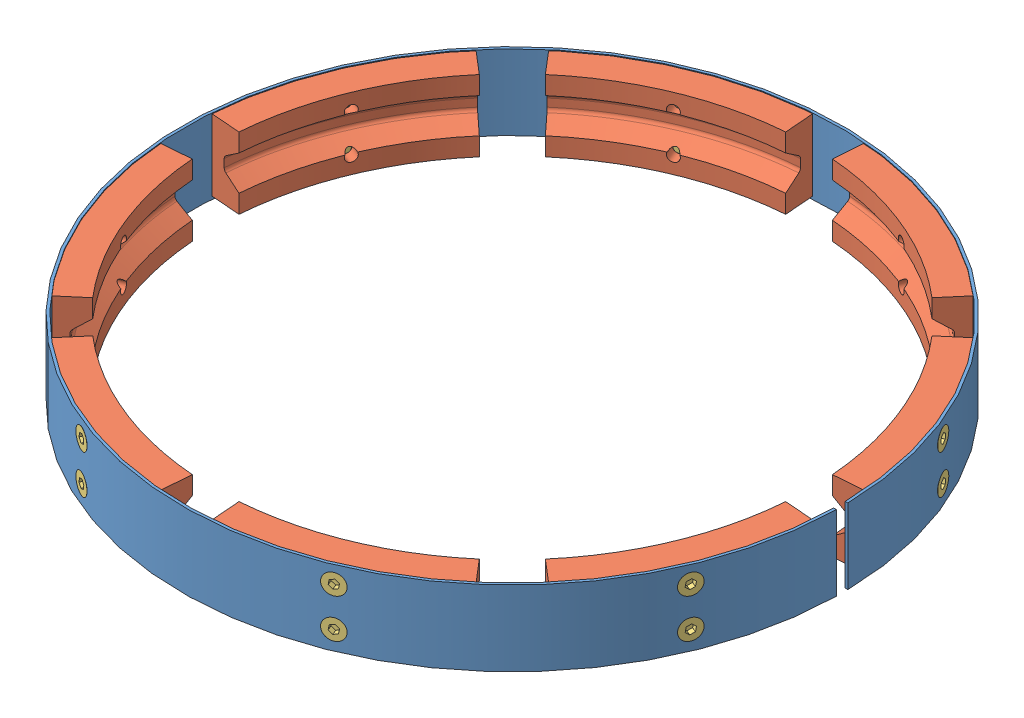
SolidWorks assembly Clampband, configuration Standard. Lengths in mm.
Overall size (127.25 14 127.25).
25 component instances, 3 part files, 6 mates.
Components (placement in the parent):
- R1-1_clampband_spring_steel-1: R1-1_clampband_spring_steel [Standard] at (28.2082 37.1213 114.6564) size (122.99 14 123)
- R1-4_clampband_clamp-1: R1-4_clampband_clamp [Standard] at (28.2082 37.3213 114.6564) x (0.92388 0 0.382683) z (-0.382683 0 0.92388) size (8.28 13.3 37.7)
- Fastener_SunkHead_M2_4-1: Fastener_SunkHead_M2_4 [Standard] at (-28.6104 33.6713 91.1214) x (0.376014 0.185879 -0.907779) z (0.071133 -0.982573 -0.171729) size (3.8 4 3.8)
- Fastener_SunkHead_M2_4-2: Fastener_SunkHead_M2_4 [Standard] at (-28.6104 40.9713 91.1214) x (0.376014 0.185879 -0.907779) z (0.071133 -0.982573 -0.171729) size (3.8 4 3.8)
- Fastener_SunkHead_M2_4-17: Fastener_SunkHead_M2_4 [Standard] at (4.6732 33.6713 57.8378) x (0.907779 0.185879 -0.376014) z (0.171729 -0.982573 -0.071133) size (3.8 4 3.8)
- Fastener_SunkHead_M2_4-18: Fastener_SunkHead_M2_4 [Standard] at (51.7432 33.6713 57.8378) x (0.907779 0.185879 0.376014) z (0.171729 -0.982573 0.071133) size (3.8 4 3.8)
- Fastener_SunkHead_M2_4-19: Fastener_SunkHead_M2_4 [Standard] at (85.0268 33.6713 91.1214) x (0.376014 0.185879 0.907779) z (0.071133 -0.982573 0.171729) size (3.8 4 3.8)
- Fastener_SunkHead_M2_4-20: Fastener_SunkHead_M2_4 [Standard] at (85.0268 33.6713 138.1915) x (-0.376014 0.185879 0.907779) z (-0.071133 -0.982573 0.171729) size (3.8 4 3.8)
- Fastener_SunkHead_M2_4-21: Fastener_SunkHead_M2_4 [Standard] at (51.7432 33.6713 171.475) x (-0.907779 0.185879 0.376014) z (-0.171729 -0.982573 0.071133) size (3.8 4 3.8)
- Fastener_SunkHead_M2_4-22: Fastener_SunkHead_M2_4 [Standard] at (4.6732 33.6713 171.475) x (-0.907779 0.185879 -0.376014) z (-0.171729 -0.982573 -0.071133) size (3.8 4 3.8)
- Fastener_SunkHead_M2_4-23: Fastener_SunkHead_M2_4 [Standard] at (-28.6104 33.6713 138.1915) x (-0.376014 0.185879 -0.907779) z (-0.071133 -0.982573 -0.171729) size (3.8 4 3.8)
- Fastener_SunkHead_M2_4-24: Fastener_SunkHead_M2_4 [Standard] at (4.6732 40.9713 57.8378) x (0.907779 0.185879 -0.376014) z (0.171729 -0.982573 -0.071133) size (3.8 4 3.8)
- Fastener_SunkHead_M2_4-25: Fastener_SunkHead_M2_4 [Standard] at (51.7432 40.9713 57.8378) x (0.907779 0.185879 0.376014) z (0.171729 -0.982573 0.071133) size (3.8 4 3.8)
- Fastener_SunkHead_M2_4-26: Fastener_SunkHead_M2_4 [Standard] at (85.0268 40.9713 91.1214) x (0.376014 0.185879 0.907779) z (0.071133 -0.982573 0.171729) size (3.8 4 3.8)
- Fastener_SunkHead_M2_4-27: Fastener_SunkHead_M2_4 [Standard] at (85.0268 40.9713 138.1915) x (-0.376014 0.185879 0.907779) z (-0.071133 -0.982573 0.171729) size (3.8 4 3.8)
- Fastener_SunkHead_M2_4-28: Fastener_SunkHead_M2_4 [Standard] at (51.7432 40.9713 171.475) x (-0.907779 0.185879 0.376014) z (-0.171729 -0.982573 0.071133) size (3.8 4 3.8)
- Fastener_SunkHead_M2_4-29: Fastener_SunkHead_M2_4 [Standard] at (4.6732 40.9713 171.475) x (-0.907779 0.185879 -0.376014) z (-0.171729 -0.982573 -0.071133) size (3.8 4 3.8)
- Fastener_SunkHead_M2_4-30: Fastener_SunkHead_M2_4 [Standard] at (-28.6104 40.9713 138.1915) x (-0.376014 0.185879 -0.907779) z (-0.071133 -0.982573 -0.171729) size (3.8 4 3.8)
- R1-4_clampband_clamp-9: R1-4_clampband_clamp [Standard] at (28.2082 37.3213 114.6564) x (0.382683 0 0.92388) z (-0.92388 0 0.382683) size (8.28 13.3 37.7)
- R1-4_clampband_clamp-10: R1-4_clampband_clamp [Standard] at (28.2082 37.3213 114.6564) x (-0.382683 0 0.92388) z (-0.92388 0 -0.382683) size (8.28 13.3 37.7)
- R1-4_clampband_clamp-11: R1-4_clampband_clamp [Standard] at (28.2082 37.3213 114.6564) x (-0.92388 0 0.382683) z (-0.382683 0 -0.92388) size (8.28 13.3 37.7)
- R1-4_clampband_clamp-12: R1-4_clampband_clamp [Standard] at (28.2082 37.3213 114.6564) x (-0.92388 0 -0.382683) z (0.382683 0 -0.92388) size (8.28 13.3 37.7)
- R1-4_clampband_clamp-13: R1-4_clampband_clamp [Standard] at (28.2082 37.3213 114.6564) x (-0.382683 0 -0.92388) z (0.92388 0 -0.382683) size (8.28 13.3 37.7)
- R1-4_clampband_clamp-14: R1-4_clampband_clamp [Standard] at (28.2082 37.3213 114.6564) x (0.382683 0 -0.92388) z (0.92388 0 0.382683) size (8.28 13.3 37.7)
- R1-4_clampband_clamp-15: R1-4_clampband_clamp [Standard] at (28.2082 37.3213 114.6564) x (0.92388 0 -0.382683) z (0.382683 0 0.92388) size (8.28 13.3 37.7)
Mates (geometry in assembly coordinates):
- Konzentrisch1: concentric anti-aligned: cylinder of R1-1_clampband_spring_steel-1 through (28.2082 37.1213 114.6564) axis (0 -1 0) radius 61; cylinder of R1-4_clampband_clamp-1 through (28.2082 44.0292 114.6564) axis (0 1 0) radius 61
- Konzentrisch2: concentric aligned: cylinder of R1-1_clampband_spring_steel-1 through (-46.0289 33.6713 83.9064) axis (0.92388 0 0.382683) radius 1.5; cylinder of R1-4_clampband_clamp-1 through (-28.1484 33.6713 91.3127) axis (0.92388 0 0.382683) radius 1
- Konzentrisch3: concentric aligned: cylinder of R1-4_clampband_clamp-1 through (-28.1484 33.6713 91.3127) axis (0.92388 0 0.382683) radius 1; cylinder of Fastener_SunkHead_M2_4-1 through (-24.9149 33.6713 92.6521) axis (0.92388 0 0.382683) radius 1
- Tangential1: tangent aligned: cylinder of R1-1_clampband_spring_steel-1 through (28.2082 37.1213 114.6564) axis (0 -1 0) radius 61.5; plane of Fastener_SunkHead_M2_4-1 through (-28.6104 33.6713 91.1214) normal (-0.92388 0 -0.382683)
- Konzentrisch4: concentric aligned: cylinder of R1-4_clampband_clamp-1 through (-28.1484 40.9713 91.3127) axis (0.92388 0 0.382683) radius 1; cylinder of Fastener_SunkHead_M2_4-2 through (-24.9149 40.9713 92.6521) axis (0.92388 0 0.382683) radius 1
- Tangential2: tangent aligned: cylinder of R1-1_clampband_spring_steel-1 through (28.2082 37.1213 114.6564) axis (0 -1 0) radius 61.5; plane of Fastener_SunkHead_M2_4-2 through (-28.6104 40.9713 91.1214) normal (-0.92388 0 -0.382683)
